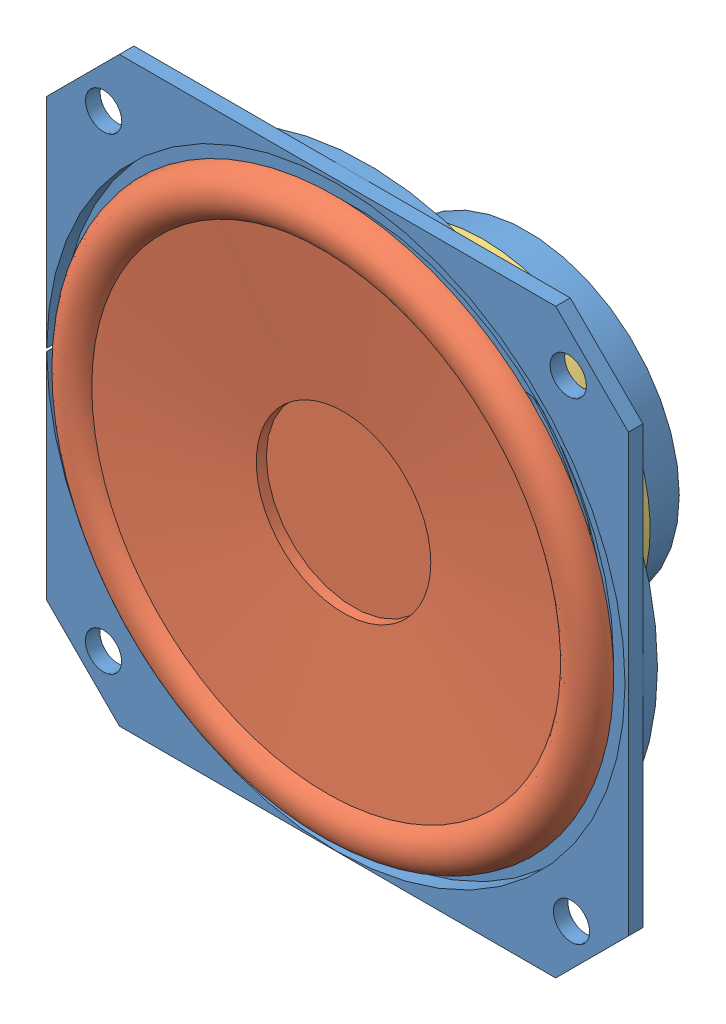
SolidWorks assembly SpeakerBagianAkhir__18, configuration Default. Lengths in mm.
Overall size (40 40 14.39).
3 component instances, 3 part files, 2 mates.
Components (placement in the parent):
- SpeakerBagian1_18-1: SpeakerBagian1_18 [Default] at (7.6602 30.1689 28.2277) size (40 40 13)
- SpeakerBagian2_18-1: SpeakerBagian2_18 [Default] at (16.4477 18.8141 27.8079) x (0 0 1) z (-1 0 0) size (3.6 38.15 38.15)
- SpeakerBagian3_18-2: SpeakerBagian3_18 [Default] at (9.5625 18.9093 19.2277) x (1 0 0) z (0 -1 0) size (23 4 23)
Mates (geometry in assembly coordinates):
- Concentric1: concentric anti-aligned: circle of SpeakerBagian1_18-1; circle of SpeakerBagian2_18-1
- Coincident2: coincident anti-aligned: circle of SpeakerBagian1_18-1; circle of SpeakerBagian3_18-2
